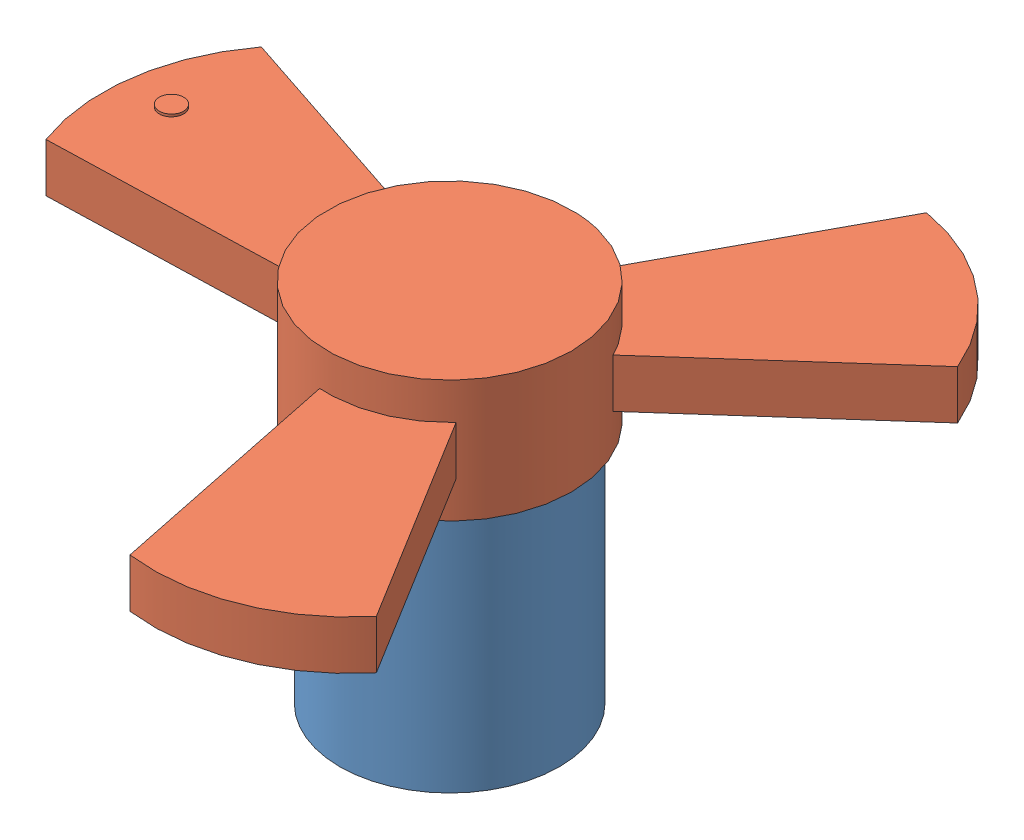
SolidWorks assembly Assem1, configuration Default. Lengths in mm.
Overall size (298.11 150 322.2).
2 component instances, 2 part files, 2 mates.
Components (placement in the parent):
- pole-1: pole [Default] at (35.6825 17.0084 101.5253) size (90 100 90)
- blade-1: blade [Default] at (35.6825 142.0084 101.5253) x (0.145196 0 -0.989403) z (0 1 0) size (287.63 259.09 50)
Mates (geometry in assembly coordinates):
- Distance1: distance = 0 mm anti-aligned: plane of blade-1 through (35.6825 117.0084 101.5253) normal (0 -1 0); plane of pole-1 through (35.6825 117.0084 101.5253) normal (0 1 0)
- Concentric1: concentric aligned: circle of pole-1; circle of blade-1
